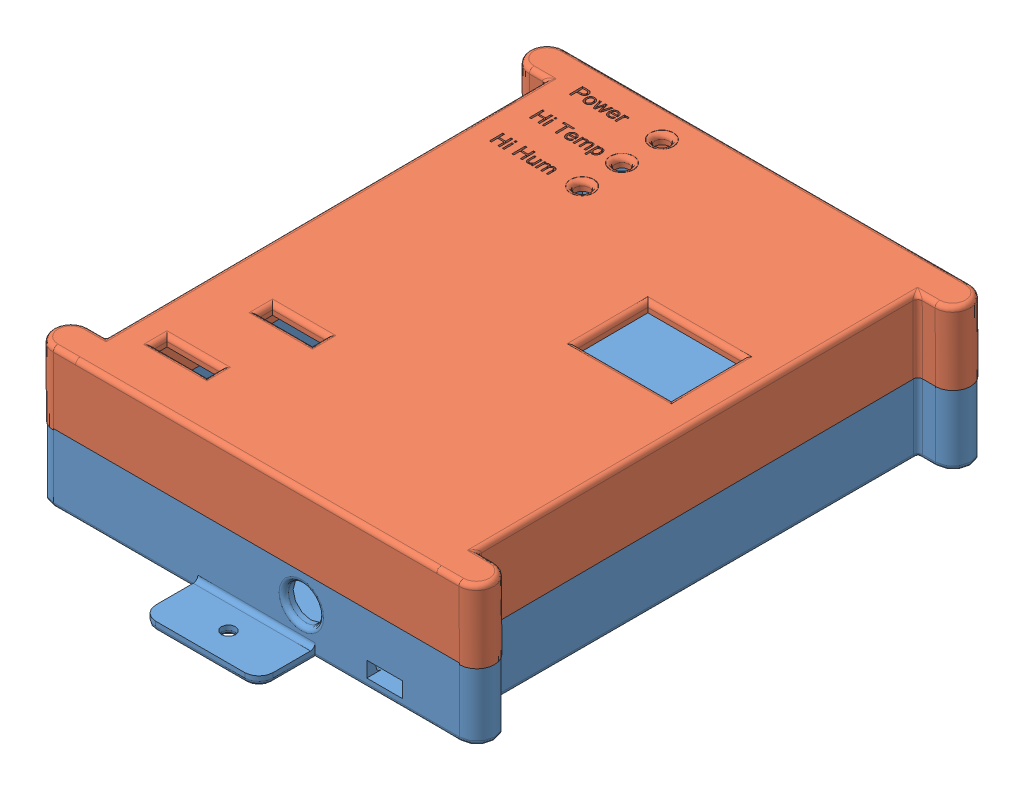
SolidWorks assembly CCBox Assembly, configuration Default. Lengths in mm.
Overall size (94 30.5 133).
2 component instances, 2 part files, 2 mates.
Components (placement in the parent):
- Climate Control Box Bottom-1: Climate Control Box Bottom [Default] at origin size (94 17 133)
- Climate Control Box Top-1: Climate Control Box Top [Default] at (0 30.1684 0.0932) x (-1 0 0) z (0 -0.006079 0.999982) size (94 15.5 109)
Mates (geometry in assembly coordinates):
- Coincident8: coincident anti-aligned: line of Climate Control Box Bottom-1 through (28.35 15 -54.5) axis (-1 0 0); line of Climate Control Box Top-1 through (-43.25 15 -54.5) axis (1 0 0)
- Distance1: distance = 0 mm aligned: plane of Climate Control Box Top-1 through (39.5 27.8371 54.5801) normal (1 0 0); plane of Climate Control Box Bottom-1 through (39.5 2 0) normal (1 0 0)
